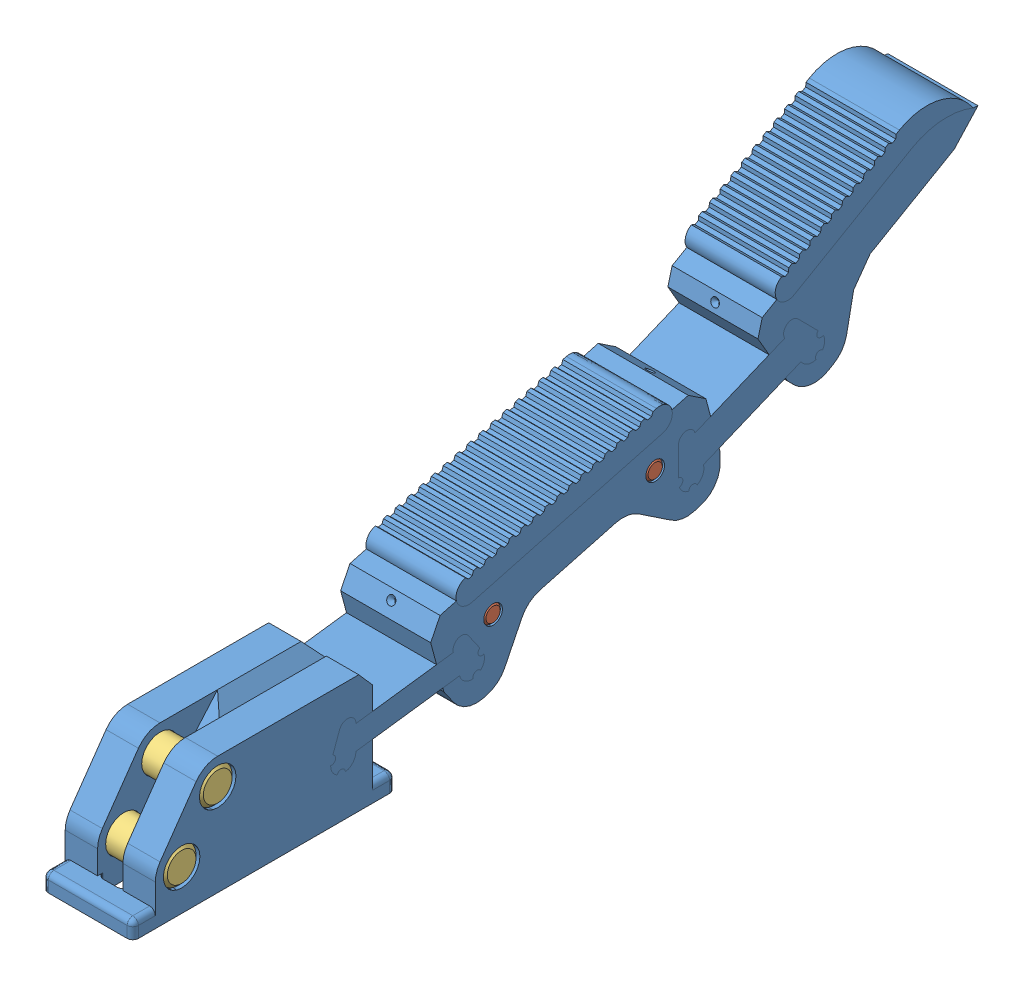
SolidWorks assembly block_finger_ff_t, configuration Default. Lengths in mm.
Overall size (19 58.78 150.92).
7 component instances, 5 part files, 12 mates.
Components (placement in the parent):
- finger_ff_t-1: finger_ff_t [Default] at origin size (19 58.78 150.92)
- 98381A472 D1-8 L5-8-1: 98381A472 D1-8 L5-8 [98381A472] at (0.0625 5.5634 -30.2193) size (15.88 3.17 3.17)
- 98381A472 D1-8 L5-8-2: 98381A472 D1-8 L5-8 [98381A472] at (0.0625 13.2775 -59.0086) size (15.88 3.17 3.17)
- 98381A539 D1-4 L5-8-1: 98381A539 D1-4 L5-8 [98381A539] at (0.0625 3.5418 18.7031) size (15.88 6.35 6.35)
- 98381A539 D1-4 L5-8-2: 98381A539 D1-4 L5-8 [98381A539] at (0.0625 -5.6082 25.11) size (15.88 6.35 6.35)
- 93365A120 4-40 insert-1: 93365A120 4-40 insert [93365A120] at (0 25.5032 -95.7226) x (1 0 0) z (0 0.812659 -0.582739) size (4.37 3.82 4.37)
- 91253A106 4-40 L1-4 countersunk-1: 91253A106 4-40 L1-4 countersunk [91253A106] at (0 24.2671 -97.4464) x (0.996599 0.066964 -0.048019) z (0 -0.582739 -0.812659) size (6.48 6.48 6.63)
Mates (geometry in assembly coordinates):
- Concentric1: concentric aligned: cylinder of finger_ff_t-1 through (-8 13.2775 -59.0086) axis (1 0 0) radius 1.6625; cylinder of 98381A472 D1-8 L5-8-2 through (-7.875 13.2775 -59.0086) axis (1 0 0) radius 1.5875
- Coincident1: coincident aligned: plane of finger_ff_t-1 through (8 0 0) normal (1 0 0); plane of 98381A472 D1-8 L5-8-2 through (8 13.2775 -59.0086) normal (1 0 0)
- Concentric2: concentric aligned: cylinder of finger_ff_t-1 through (-8 5.5634 -30.2193) axis (1 0 0) radius 1.6625; cylinder of 98381A472 D1-8 L5-8-1 through (-7.875 5.5634 -30.2193) axis (1 0 0) radius 1.5875
- Coincident2: coincident aligned: plane of finger_ff_t-1 through (8 0 0) normal (1 0 0); plane of 98381A472 D1-8 L5-8-1 through (8 5.5634 -30.2193) normal (1 0 0)
- Concentric3: concentric aligned: cylinder of finger_ff_t-1 through (-8 3.5418 18.7031) axis (1 0 0) radius 3.25; cylinder of 98381A539 D1-4 L5-8-1 through (-7.875 3.5418 18.7031) axis (1 0 0) radius 3.175
- Coincident3: coincident aligned: plane of finger_ff_t-1 through (8 0 0) normal (1 0 0); plane of 98381A539 D1-4 L5-8-1 through (8 3.5418 18.7031) normal (1 0 0)
- Concentric4: concentric aligned: cylinder of finger_ff_t-1 through (-8 -5.6082 25.11) axis (1 0 0) radius 3.25; cylinder of 98381A539 D1-4 L5-8-2 through (-7.875 -5.6082 25.11) axis (1 0 0) radius 3.175
- Coincident4: coincident aligned: plane of finger_ff_t-1 through (8 0 0) normal (1 0 0); plane of 98381A539 D1-4 L5-8-2 through (8 -5.6082 25.11) normal (1 0 0)
- Concentric5: concentric aligned: cylinder of finger_ff_t-1 through (0 28.1256 -92.0656) axis (0 -0.582739 -0.812659) radius 1.85; circle of 93365A120 4-40 insert-1
- Coincident5: coincident aligned: plane of finger_ff_t-1 through (-13 27.5349 -97.1794) normal (0 -0.582739 -0.812659); plane of 93365A120 4-40 insert-1 through (0 25.5032 -95.7226) normal (0 -0.582739 -0.812659)
- Concentric6: concentric anti-aligned: circle of 93365A120 4-40 insert-1; circle of 91253A106 4-40 L1-4 countersunk-1
- Coincident6: coincident: circle of 93365A120 4-40 insert-1; cone of 91253A106 4-40 L1-4 countersunk-1 through (0 25.4957 -95.7331) axis (0 0.582739 0.812659)
